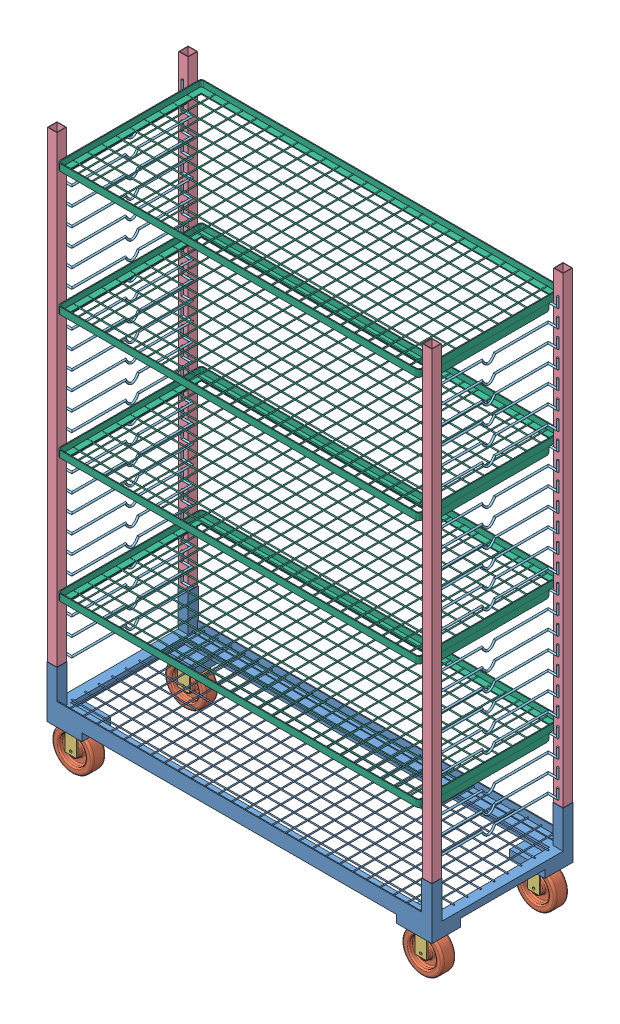
SolidWorks assembly cart_assembly, configuration Default. Lengths in mm.
Overall size (1465.58 2082.8 540.51).
71 component instances, 6 part files, 15 mates.
Components (placement in the parent):
- base-1: base [Default] at (534.0064 765.885 1057.2347) size (1444.62 194.06 530.22)
- wheel_assembly-1: wheel_assembly [Default] at (8.6921 764.7646 844.3099) x (0 0 -1) z (-1 0 0) size (99.57 177.8 152.4)
  - wheel-1: wheel [Default] at (-26.5523 104.0356 130.9582) size (50.8 152.4 152.4)
  - wheel_housing-1: wheel_housing [Default] at (48.6317 2.4356 193.4422) x (0 1 0) z (0 0 1) size (114.3 99.57 124.97)
- wheel_assembly-2: wheel_assembly [Default] at (1321.8721 764.7646 844.3099) x (0 0 -1) z (-1 0 0) size (99.57 177.8 152.4)
  - wheel-1: wheel [Default] at (-26.5523 104.0356 130.9582) size (50.8 152.4 152.4)
  - wheel_housing-1: wheel_housing [Default] at (48.6317 2.4356 193.4422) x (0 1 0) z (0 0 1) size (114.3 99.57 124.97)
- wheel_assembly-3: wheel_assembly [Default] at (8.6921 764.7646 1267.2199) x (0 0 -1) z (-1 0 0) size (99.57 177.8 152.4)
  - wheel-1: wheel [Default] at (-26.5523 104.0356 130.9582) size (50.8 152.4 152.4)
  - wheel_housing-1: wheel_housing [Default] at (48.6317 2.4356 193.4422) x (0 1 0) z (0 0 1) size (114.3 99.57 124.97)
- wheel_assembly-4: wheel_assembly [Default] at (1321.8721 764.7646 1267.2199) x (0 0 -1) z (-1 0 0) size (99.57 177.8 152.4)
  - wheel-1: wheel [Default] at (-26.5523 104.0356 130.9582) size (50.8 152.4 152.4)
  - wheel_housing-1: wheel_housing [Default] at (48.6317 2.4356 193.4422) x (0 1 0) z (0 0 1) size (114.3 99.57 124.97)
- side_assembly-1: side_assembly [Default] at (3135.9189 1569.601 1280.3971) x (0 0 1) z (-1 0 0) size (527.68 1898.65 55.7)
  - side-1: side [Default] at (-485.354 -800.922 1914.779) size (527.68 1898.65 35.56)
  - cross_bar-2: cross_bar [Default] at (-448.2065 -580.3312 1897.771) size (456.56 60.39 42.04)
  - cross_bar-3: cross_bar [Default] at (-448.2065 -513.7832 1897.771) size (456.56 60.39 42.04)
  - cross_bar-4: cross_bar [Default] at (-448.2065 -447.2352 1897.771) size (456.56 60.39 42.04)
  - cross_bar-5: cross_bar [Default] at (-448.2065 -380.6872 1897.771) size (456.56 60.39 42.04)
  - cross_bar-6: cross_bar [Default] at (-448.2065 -314.1392 1897.771) size (456.56 60.39 42.04)
  - cross_bar-7: cross_bar [Default] at (-448.2065 -247.5912 1897.771) size (456.56 60.39 42.04)
  - cross_bar-8: cross_bar [Default] at (-448.2065 -181.0432 1897.771) size (456.56 60.39 42.04)
  - cross_bar-9: cross_bar [Default] at (-448.2065 -114.4952 1897.771) size (456.56 60.39 42.04)
  - cross_bar-10: cross_bar [Default] at (-448.2065 -47.9472 1897.771) size (456.56 60.39 42.04)
  - cross_bar-11: cross_bar [Default] at (-448.2065 18.6008 1897.771) size (456.56 60.39 42.04)
  - cross_bar-12: cross_bar [Default] at (-448.2065 85.1488 1897.771) size (456.56 60.39 42.04)
  - cross_bar-13: cross_bar [Default] at (-448.2065 151.6968 1897.771) size (456.56 60.39 42.04)
  - cross_bar-14: cross_bar [Default] at (-448.2065 218.2448 1897.771) size (456.56 60.39 42.04)
  - cross_bar-15: cross_bar [Default] at (-448.2065 284.7928 1897.771) size (456.56 60.39 42.04)
  - cross_bar-16: cross_bar [Default] at (-448.2065 351.3408 1897.771) size (456.56 60.39 42.04)
  - cross_bar-17: cross_bar [Default] at (-448.2065 417.8888 1897.771) size (456.56 60.39 42.04)
  - cross_bar-18: cross_bar [Default] at (-448.2065 484.4368 1897.771) size (456.56 60.39 42.04)
  - cross_bar-19: cross_bar [Default] at (-448.2065 550.9848 1897.771) size (456.56 60.39 42.04)
  - cross_bar-20: cross_bar [Default] at (-448.2065 617.5328 1897.771) size (456.56 60.39 42.04)
  - cross_bar-21: cross_bar [Default] at (-448.2065 684.0808 1897.771) size (456.56 60.39 42.04)
  - cross_bar-22: cross_bar [Default] at (-448.2065 750.6288 1897.771) size (456.56 60.39 42.04)
  - cross_bar-23: cross_bar [Default] at (-448.2065 817.1768 1897.771) size (456.56 60.39 42.04)
  - cross_bar-24: cross_bar [Default] at (-448.2065 883.7248 1897.771) size (456.56 60.39 42.04)
  - cross_bar-25: cross_bar [Default] at (-448.2065 950.2728 1897.771) size (456.56 60.39 42.04)
  - cross_bar-26: cross_bar [Default] at (-448.2065 1016.8208 1897.771) size (456.56 60.39 42.04)
- side_assembly-2: side_assembly [Default] at (-2067.9061 1569.601 834.0722) x (0 0 -1) z (1 0 0) size (527.68 1898.65 55.7)
  - side-1: side [Default] at (-485.354 -800.922 1914.779) size (527.68 1898.65 35.56)
  - cross_bar-2: cross_bar [Default] at (-448.2065 -580.3312 1897.771) size (456.56 60.39 42.04)
  - cross_bar-3: cross_bar [Default] at (-448.2065 -513.7832 1897.771) size (456.56 60.39 42.04)
  - cross_bar-4: cross_bar [Default] at (-448.2065 -447.2352 1897.771) size (456.56 60.39 42.04)
  - cross_bar-5: cross_bar [Default] at (-448.2065 -380.6872 1897.771) size (456.56 60.39 42.04)
  - cross_bar-6: cross_bar [Default] at (-448.2065 -314.1392 1897.771) size (456.56 60.39 42.04)
  - cross_bar-7: cross_bar [Default] at (-448.2065 -247.5912 1897.771) size (456.56 60.39 42.04)
  - cross_bar-8: cross_bar [Default] at (-448.2065 -181.0432 1897.771) size (456.56 60.39 42.04)
  - cross_bar-9: cross_bar [Default] at (-448.2065 -114.4952 1897.771) size (456.56 60.39 42.04)
  - cross_bar-10: cross_bar [Default] at (-448.2065 -47.9472 1897.771) size (456.56 60.39 42.04)
  - cross_bar-11: cross_bar [Default] at (-448.2065 18.6008 1897.771) size (456.56 60.39 42.04)
  - cross_bar-12: cross_bar [Default] at (-448.2065 85.1488 1897.771) size (456.56 60.39 42.04)
  - cross_bar-13: cross_bar [Default] at (-448.2065 151.6968 1897.771) size (456.56 60.39 42.04)
  - cross_bar-14: cross_bar [Default] at (-448.2065 218.2448 1897.771) size (456.56 60.39 42.04)
  - cross_bar-15: cross_bar [Default] at (-448.2065 284.7928 1897.771) size (456.56 60.39 42.04)
  - cross_bar-16: cross_bar [Default] at (-448.2065 351.3408 1897.771) size (456.56 60.39 42.04)
  - cross_bar-17: cross_bar [Default] at (-448.2065 417.8888 1897.771) size (456.56 60.39 42.04)
  - cross_bar-18: cross_bar [Default] at (-448.2065 484.4368 1897.771) size (456.56 60.39 42.04)
  - cross_bar-19: cross_bar [Default] at (-448.2065 550.9848 1897.771) size (456.56 60.39 42.04)
  - cross_bar-20: cross_bar [Default] at (-448.2065 617.5328 1897.771) size (456.56 60.39 42.04)
  - cross_bar-21: cross_bar [Default] at (-448.2065 684.0808 1897.771) size (456.56 60.39 42.04)
  - cross_bar-22: cross_bar [Default] at (-448.2065 750.6288 1897.771) size (456.56 60.39 42.04)
  - cross_bar-23: cross_bar [Default] at (-448.2065 817.1768 1897.771) size (456.56 60.39 42.04)
  - cross_bar-24: cross_bar [Default] at (-448.2065 883.7248 1897.771) size (456.56 60.39 42.04)
  - cross_bar-25: cross_bar [Default] at (-448.2065 950.2728 1897.771) size (456.56 60.39 42.04)
  - cross_bar-26: cross_bar [Default] at (-448.2065 1016.8208 1897.771) size (456.56 60.39 42.04)
- shelf-1: shelf [Default] at (534.0064 1160.1482 1057.1077) size (1356.49 50.8 540.51)
- shelf-2: shelf [Default] at (534.0064 1625.9842 1057.1077) size (1356.49 50.8 540.51)
- shelf-3: shelf [Default] at (534.0064 2091.8202 1057.1077) size (1356.49 50.8 540.51)
- shelf-4: shelf [Default] at (534.0064 2557.6562 1057.1077) size (1356.49 50.8 540.51)
Mates (geometry in assembly coordinates):
- Coincident1: coincident: plane of base-1 through (534.0064 762.329 1057.2347) normal (0 -1 0); plane of ? through (-184.7501 762.329 1219.2232) normal (0 1 0)
- Coincident2: coincident anti-aligned: plane of base-1 through (-59.7821 736.929 1318.7912) normal (-1 0 0); plane of ? through (-59.7821 755.979 1219.2232) normal (1 0 0)
- Coincident3: coincident anti-aligned: plane of base-1 through (-184.7501 736.929 1219.2232) normal (0 0 1); plane of ? through (-184.7501 755.979 1219.2232) normal (0 0 -1)
- Coincident4: coincident anti-aligned: plane of base-1 through (534.0064 762.329 1057.2347) normal (0 -1 0); plane of wheel_assembly-1/wheel_housing-1 through (-184.7501 762.329 795.6782) normal (0 1 0)
- Coincident5: coincident anti-aligned: plane of base-1 through (-184.7501 736.929 795.6782) normal (1 0 0); plane of wheel_assembly-1/wheel_housing-1 through (-184.7501 755.979 795.6782) normal (-1 0 0)
- Coincident6: coincident anti-aligned: plane of base-1 through (-184.7501 736.929 895.2462) normal (0 0 -1); plane of wheel_assembly-1/wheel_housing-1 through (-184.7501 755.979 895.2462) normal (0 0 1)
- Coincident7: coincident anti-aligned: plane of base-1 through (1255.0489 930.985 793.3922) normal (-1 0 0); plane of side_assembly-1/side-1 through (1255.0489 2667.329 793.3922) normal (1 0 0)
- Coincident8: coincident anti-aligned: plane of base-1 through (1255.0489 930.985 793.3922) normal (0 0 1); plane of side_assembly-1/side-1 through (1219.4889 2667.329 793.3922) normal (0 0 -1)
- Coincident10: coincident anti-aligned: plane of base-1 through (534.0064 768.679 1057.2347) normal (0 1 0); plane of side_assembly-1/side-1 through (1221.1399 768.679 795.0432) normal (0 -1 0)
- Coincident11: coincident anti-aligned: plane of base-1 through (-187.0361 930.985 793.3922) normal (0 0 1); plane of side_assembly-2/side-1 through (-151.4761 2667.329 793.3922) normal (0 0 -1)
- Coincident12: coincident anti-aligned: plane of base-1 through (-187.0361 930.985 793.3922) normal (1 0 0); plane of side_assembly-2/side-1 through (-187.0361 2667.329 828.9522) normal (-1 0 0)
- Coincident13: coincident anti-aligned: plane of base-1 through (534.0064 768.679 1057.2347) normal (0 1 0); plane of side_assembly-2/side-1 through (-153.1271 768.679 1319.4262) normal (0 -1 0)
- Distance1: distance = 7.239 mm anti-aligned: plane of shelf-1 through (-144.2371 1181.9922 1316.1877) normal (-1 0 0); plane of side_assembly-2/side-1 through (-151.4761 2667.329 1321.0772) normal (1 0 0)
- Distance2: distance = 6.2865 mm aligned: plane of shelf-1 through (-133.0611 1181.9922 1327.3637) normal (0 0 1); plane of side_assembly-1/side-1 through (1219.4889 2667.329 1321.0772) normal (0 0 1)
- Tangent1: tangent anti-aligned: cylinder of side_assembly-2/cross_bar-5 through (-134.575 1153.3537 1289.5034) axis (0 0 -1) radius 3.2385; plane of shelf-1 through (1201.0739 1156.5922 1316.1877) normal (0 -1 0)
